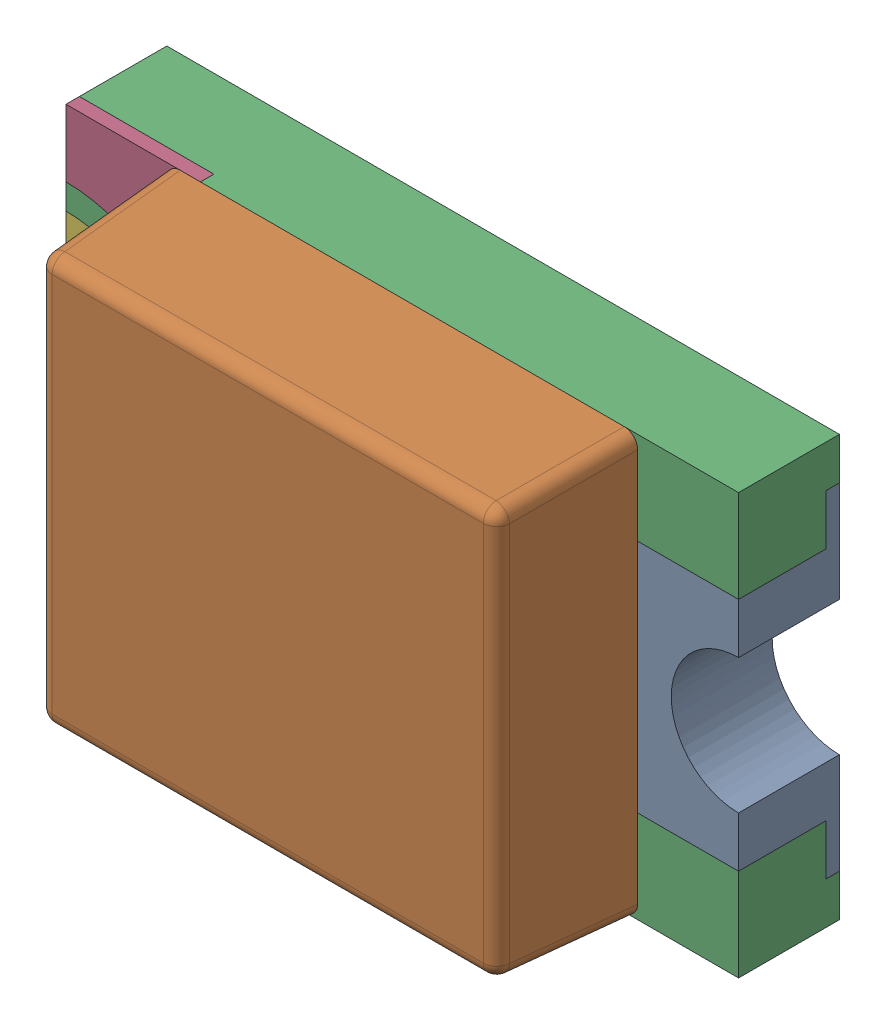
SolidWorks assembly D6, configuration Standard. Lengths in mm.
Overall size (2 1.25 0.7).
7 component instances, 5 part files, 0 mates.
Components (placement in the parent):
- WL-SMCW_0805_LED-1: WL-SMCW_0805_LED [Standard] at (12.1002 22.4402 -0.02) x (1 0 0) z (0 0 1) size (2 1.25 0.7)
  - base-1: base [Standard] at (0.8 0 0) x (-1 0 0) z (0 0 1) size (0.4 1 0.3)
  - cover-1: cover [Standard] at (0 0 0.3) size (1.4 1.25 0.4)
  - housing_3-1: housing_3 [Standard] at origin size (2 1.25 0.3)
  - marking-1: marking [Standard] at (-0.8 0.525 0.26) size (0.4 0.48 0.04)
  - marking-2: marking [Standard] at (-0.8 -0.525 0.3) x (1 0 0) z (0 0 -1) size (0.4 0.48 0.04)
  - base_2-1: base_2 [Standard] at (-0.8 0 0) size (0.4 1 0.3)
